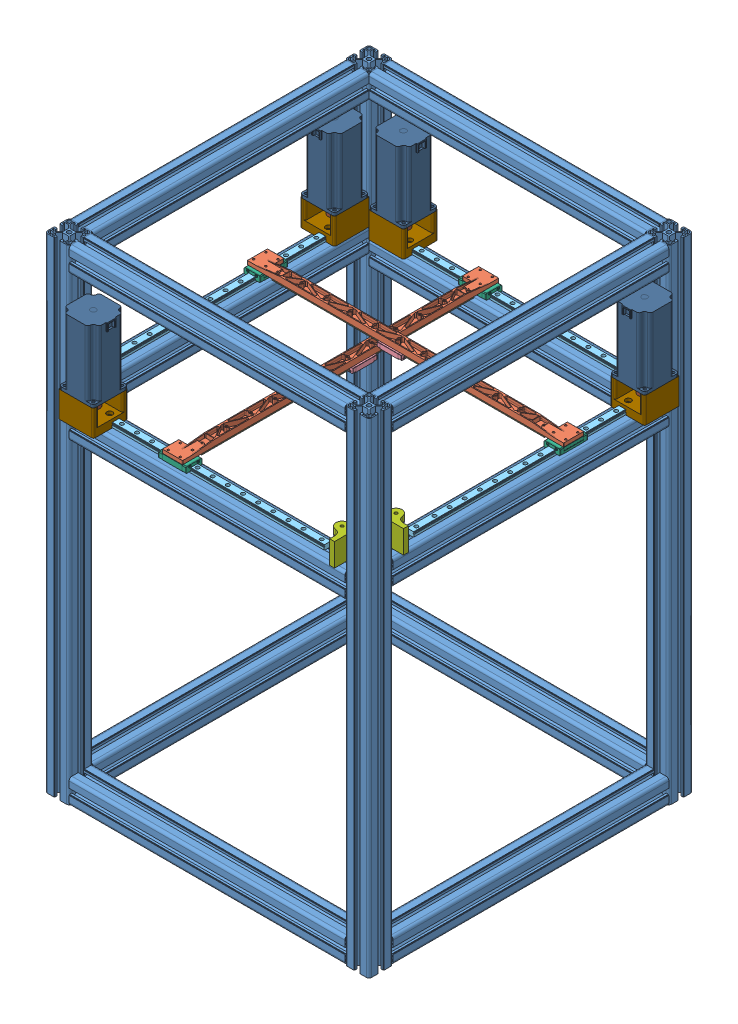
SolidWorks assembly Sp33der, configuration Default. Lengths in mm.
Overall size (569 800 569).
74 component instances, 11 part files, 6 mates.
Components (placement in the parent):
- Frame-1: Frame [Default] at origin size (535 800 535) (flexible)
  - 4040 Aluminium extrusion-1: 4040 Aluminium extrusion [Lenght 800mm] at (-247.5 0 -247.5) x (-1 0 0) z (0 1 0) size (40 40 800)
  - 4040 Aluminium extrusion-2: 4040 Aluminium extrusion [Lenght 800mm] at (247.5 0 -247.5) x (0 0 -1) z (0 1 0) size (40 40 800)
  - 4040 Aluminium extrusion-3: 4040 Aluminium extrusion [Lenght 800mm] at (247.5 0 247.5) x (0 0 1) z (0 1 0) size (40 40 800)
  - 4040 Aluminium extrusion-4: 4040 Aluminium extrusion [Lenght 800mm] at (-247.5 0 247.5) x (0 0 -1) z (0 1 0) size (40 40 800)
  - 4040 Aluminium extrusion-5: 4040 Aluminium extrusion [455] at (247.5 780 -227.5) size (40 40 455)
  - 4040 Aluminium extrusion-6: 4040 Aluminium extrusion [455] at (247.5 20 -227.5) size (40 40 455)
  - 4040 Aluminium extrusion-7: 4040 Aluminium extrusion [455] at (-227.5 20 -247.5) x (0 0 -1) z (1 0 0) size (40 40 455)
  - 4040 Aluminium extrusion-11: 4040 Aluminium extrusion [455] at (-247.5 20 -227.5) size (40 40 455)
  - 4040 Aluminium extrusion-12: 4040 Aluminium extrusion [455] at (-247.5 780 -227.5) size (40 40 455)
  - 4040 Aluminium extrusion-13: 4040 Aluminium extrusion [455] at (-227.5 20 247.5) x (0 0 -1) z (1 0 0) size (40 40 455)
  - 4040 Aluminium extrusion-14: 4040 Aluminium extrusion [455] at (-227.5 780 247.5) x (0 0 -1) z (1 0 0) size (40 40 455)
  - 4040 Aluminium extrusion-15: 4040 Aluminium extrusion [455] at (-227.5 780 -247.5) x (0 0 -1) z (1 0 0) size (40 40 455)
- XY Gantry-1: XY Gantry [Default] at (0 580 0) size (569 214.5 569) (flexible)
  - XGantry-1: XGantry [Default] at origin size (569 196 455) (flexible)
    - Bar Assembly^XGantry-1: Bar Assembly^XGantry [Default] at (0 16 -69.1674) x (-1 0 0) z (0 0 -1) size (522 20 34.2) (flexible)
      - MotionSystemXBarLean_Sp33der-1: MotionSystemXBarLean_Sp33der [Default] at origin size (522 10 33.2)
      - MGN9-250-1: MGN9-250 [По умолчанию] at (225 528.8912 -9.4887) x (0 0 -1) z (-1 0 0) size (20 10 450) (flexible)
        - MGN9-1: MGN9 [450] at (-9.4887 535.1412 0) size (9 6.5 450)
        - MGN9-H-1: MGN9-H [По умолчанию] at (-9.4887 537.8912 199.1493) size (20 8 40.67)
    - XYRail Assembly-1: XYRail Assembly [Left] at (-247.5 -20 0) size (57 196 455) (flexible)
      - MGN12 Assembly-1: MGN12 Assembly [2 X 12C] at (0 20 4.5) size (27 13.07 350) (flexible)
        - MGN12 LINEAR GUIDE RAIL, CONFIGURABLE-1: MGN12 LINEAR GUIDE RAIL, CONFIGURABLE [350 mm] at (0 5.5 0) size (11.97 8.07 350)
        - MGN12H, LINEAR GUIDE BLOCK-1: MGN12H, LINEAR GUIDE BLOCK [Default] at (0 5.5 -81.6674) size (27 10 47.52)
      - 4040 Aluminium extrusion-1: 4040 Aluminium extrusion [455] at (0 0 -227.5) size (40 40 455)
      - Idler Assembly-1: Idler Assembly [Right] at (-8.5 53.2 227.5) x (-1 0 0) z (0 0 -1) size (57 38 29.01)
        - Idler Bracket^Idler Assembly-1: Idler Bracket^Idler Assembly [Right] at origin size (57 38 26) (virtual)
        - GT2 IdlerT24 W12 Ø10_Printable-1: GT2 IdlerT24 W12 Ø10_Printable [W12 Ø5] at (0 8 16) x (0.927724 0 -0.373267) z (0 -1 0) size (20 20 16)
      - Stepper Assembly-1: Stepper Assembly [Left] at (-8.5 20 -199) x (0 0 -1) z (1 0 0) size (59 156 57)
        - Stepper Mount^XGantry_XY Gantry_Sp33der-1: Stepper Mount^XGantry_XY Gantry_Sp33der [Left] at origin size (57 43 57)
        - Nema 23 113mm body -1: Nema 23 113mm body  [Default] at (0 156 0) x (0 0 1) z (0 -1 0) size (57 59 137)
        - GT2_T24_W12_Ø10-1: GT2_T24_W12_Ø10 [Default] at (0 19 0) x (-0.694269 0 0.719715) z (0 1 0) size (20 20 21.8)
    - XYRail Assembly-2: XYRail Assembly [Right] at (247.5 -20 0) size (57 196 455) (flexible)
      - MGN12 Assembly-1: MGN12 Assembly [2 X 12C] at (0 20 4.5) size (27 13.07 350) (flexible)
        - MGN12 LINEAR GUIDE RAIL, CONFIGURABLE-1: MGN12 LINEAR GUIDE RAIL, CONFIGURABLE [350 mm] at (0 5.5 0) size (11.97 8.07 350)
        - MGN12H, LINEAR GUIDE BLOCK-1: MGN12H, LINEAR GUIDE BLOCK [Default] at (0 5.5 -81.6674) size (27 10 47.52)
      - 4040 Aluminium extrusion-1: 4040 Aluminium extrusion [455] at (0 0 -227.5) size (40 40 455)
      - Idler Assembly-1: Idler Assembly [Left] at (8.5 53.2 227.5) x (-1 0 0) z (0 0 -1) size (57 38 29.01)
        - Idler Bracket^Idler Assembly-1: Idler Bracket^Idler Assembly [Left] at origin size (57 38 26) (virtual)
        - GT2 IdlerT24 W12 Ø10_Printable-1: GT2 IdlerT24 W12 Ø10_Printable [W12 Ø5] at (0 8 16) x (0.927724 0 -0.373267) z (0 -1 0) size (20 20 16)
      - Stepper Assembly-1: Stepper Assembly [Right] at (8.5 20 -199) x (0 0 -1) z (1 0 0) size (59 156 57)
        - Stepper Mount^XGantry_XY Gantry_Sp33der-1: Stepper Mount^XGantry_XY Gantry_Sp33der [Right] at origin size (57 43 57)
        - Nema 23 113mm body -1: Nema 23 113mm body  [Default] at (0 156 0) x (0 0 1) z (0 -1 0) size (57 59 137)
        - GT2_T24_W12_Ø10-1: GT2_T24_W12_Ø10 [Default] at (0 19 0) x (-0.694269 0 0.719715) z (0 1 0) size (20 20 21.8)
  - XGantry-2: XGantry [Default] at (0 -18.5 0) x (0 0 -1) z (1 0 0) size (569 196 455) (flexible)
    - Bar Assembly^XGantry-1: Bar Assembly^XGantry [Default] at (0 16 -55.8007) x (-1 0 0) z (0 0 -1) size (522 20 34.2) (flexible)
      - MotionSystemXBarLean_Sp33der-1: MotionSystemXBarLean_Sp33der [Default] at origin size (522 10 33.2)
      - MGN9-250-1: MGN9-250 [По умолчанию] at (-225 528.8912 -21.9894) x (0 0 1) z (1 0 0) size (20 10 450) (flexible)
        - MGN9-1: MGN9 [450] at (21.9894 535.1412 450) x (-1 0 0) z (0 0 -1) size (9 6.5 450)
        - MGN9-H-1: MGN9-H [По умолчанию] at (21.9894 537.8912 185.7826) x (-1 0 0) z (0 0 -1) size (20 8 40.67)
    - XYRail Assembly-1: XYRail Assembly [Left] at (-247.5 -20 0) size (57 196 455) (flexible)
      - MGN12 Assembly-1: MGN12 Assembly [2 X 12C] at (0 20 4.5) size (27 13.07 350) (flexible)
        - MGN12 LINEAR GUIDE RAIL, CONFIGURABLE-1: MGN12 LINEAR GUIDE RAIL, CONFIGURABLE [350 mm] at (0 5.5 0) size (11.97 8.07 350)
        - MGN12H, LINEAR GUIDE BLOCK-1: MGN12H, LINEAR GUIDE BLOCK [Default] at (0 5.5 -68.3007) size (27 10 47.52)
      - 4040 Aluminium extrusion-1: 4040 Aluminium extrusion [455] at (0 0 -227.5) size (40 40 455)
      - Idler Assembly-1: Idler Assembly [Right] at (-8.5 53.2 227.5) x (-1 0 0) z (0 0 -1) size (57 38 29.01)
        - Idler Bracket^Idler Assembly-1: Idler Bracket^Idler Assembly [Right] at origin size (57 38 26) (virtual)
        - GT2 IdlerT24 W12 Ø10_Printable-1: GT2 IdlerT24 W12 Ø10_Printable [W12 Ø5] at (0 8 16) x (0.927724 0 -0.373267) z (0 -1 0) size (20 20 16)
      - Stepper Assembly-1: Stepper Assembly [Left] at (-8.5 20 -199) x (0 0 -1) z (1 0 0) size (59 156 57)
        - Stepper Mount^XGantry_XY Gantry_Sp33der-1: Stepper Mount^XGantry_XY Gantry_Sp33der [Left] at origin size (57 43 57)
        - Nema 23 113mm body -1: Nema 23 113mm body  [Default] at (0 156 0) x (0 0 1) z (0 -1 0) size (57 59 137)
        - GT2_T24_W12_Ø10-1: GT2_T24_W12_Ø10 [Default] at (0 19 0) x (-0.694269 0 0.719715) z (0 1 0) size (20 20 21.8)
    - XYRail Assembly-2: XYRail Assembly [Right] at (247.5 -20 0) size (57 196 455) (flexible)
      - MGN12 Assembly-1: MGN12 Assembly [2 X 12C] at (0 20 4.5) size (27 13.07 350) (flexible)
        - MGN12 LINEAR GUIDE RAIL, CONFIGURABLE-1: MGN12 LINEAR GUIDE RAIL, CONFIGURABLE [350 mm] at (0 5.5 0) size (11.97 8.07 350)
        - MGN12H, LINEAR GUIDE BLOCK-1: MGN12H, LINEAR GUIDE BLOCK [Default] at (0 5.5 -68.3007) size (27 10 47.52)
      - 4040 Aluminium extrusion-1: 4040 Aluminium extrusion [455] at (0 0 -227.5) size (40 40 455)
      - Idler Assembly-1: Idler Assembly [Left] at (8.5 53.2 227.5) x (-1 0 0) z (0 0 -1) size (57 38 29.01)
        - Idler Bracket^Idler Assembly-1: Idler Bracket^Idler Assembly [Left] at origin size (57 38 26) (virtual)
        - GT2 IdlerT24 W12 Ø10_Printable-1: GT2 IdlerT24 W12 Ø10_Printable [W12 Ø5] at (0 8 16) x (0.927724 0 -0.373267) z (0 -1 0) size (20 20 16)
      - Stepper Assembly-1: Stepper Assembly [Right] at (8.5 20 -199) x (0 0 -1) z (1 0 0) size (59 156 57)
        - Stepper Mount^XGantry_XY Gantry_Sp33der-1: Stepper Mount^XGantry_XY Gantry_Sp33der [Right] at origin size (57 43 57)
        - Nema 23 113mm body -1: Nema 23 113mm body  [Default] at (0 156 0) x (0 0 1) z (0 -1 0) size (57 59 137)
        - GT2_T24_W12_Ø10-1: GT2_T24_W12_Ø10 [Default] at (0 19 0) x (-0.694269 0 0.719715) z (0 1 0) size (20 20 21.8)
Mates (geometry in assembly coordinates):
- Coincident87: coincident aligned: plane of XY Gantry-1/XGantry-1 through (0 580 0) normal (0 0 1)
- Coincident88: coincident aligned: plane of XY Gantry-1/XGantry-1 through (0 580 0) normal (1 0 0)
- Coincident99: coincident aligned: plane of Frame-1 through (0 0 0) normal (0 0 1)
- Coincident100: coincident aligned: plane of Frame-1 through (0 0 0) normal (1 0 0)
- Coincident101: coincident aligned: plane of Frame-1 through (0 0 0) normal (0 1 0)
- Distance1: distance = 180 mm anti-aligned: plane of XY Gantry-1/XGantry-1/XYRail Assembly-2/4040 Aluminium extrusion-1 through (247.5 580 227.5) normal (0 1 0); plane of Frame-1/4040 Aluminium extrusion-5 through (247.5 760 227.5) normal (0 -1 0)
